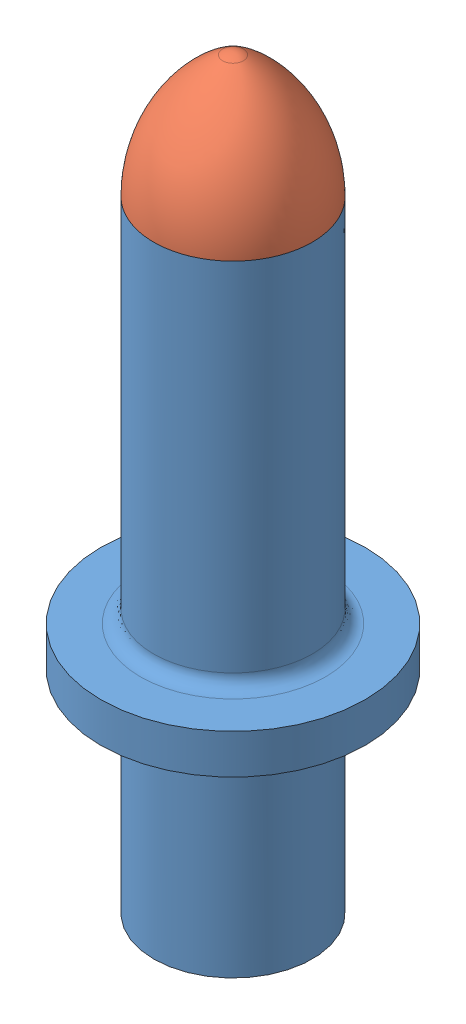
SolidWorks assembly Impact Anvil 2.2, configuration Default. Lengths in mm.
Overall size (50.8 179.39 50.8).
2 component instances, 2 part files, 6 mates.
Components (placement in the parent):
- Impact Weight-2: Impact Weight [Default] at origin size (63.5 149.22 63.5)
- Impact Nose-2: Impact Nose [Default] at (0 120.8584 0) size (38.1 30.16 38.1)
Mates (geometry in assembly coordinates):
- Coincident1: coincident: plane of Impact Weight-1 through (85.7531 7.7352 109.8081) normal (1 0 0); plane of Impact Nose-1 through (85.7531 196.1554 109.8081) normal (1 0 0)
- Coincident2: coincident: plane of Impact Weight-1 through (85.7531 7.7352 109.8081) normal (0 0 -1); plane of Impact Nose-1 through (85.7531 196.1554 109.8081) normal (0 0 -1)
- Coincident3: coincident anti-aligned: plane of Impact Weight-1 through (66.7031 156.9602 109.8081) normal (0 1 0); plane of Impact Nose-1 through (85.7531 156.9602 109.8081) normal (0 -1 0)
- Coincident4: coincident: plane of Impact Weight-2 through (0 -53.7666 0) normal (1 0 0); plane of Impact Nose-2 through (0 125.6209 0) normal (1 0 0)
- Coincident5: coincident: plane of Impact Weight-2 through (0 -53.7666 0) normal (0 0 -1); plane of Impact Nose-2 through (0 125.6209 0) normal (0 0 -1)
- Coincident6: coincident anti-aligned: plane of Impact Weight-2 through (-19.05 95.4584 0) normal (0 1 0); plane of Impact Nose-2 through (0 95.4584 0) normal (0 -1 0)
